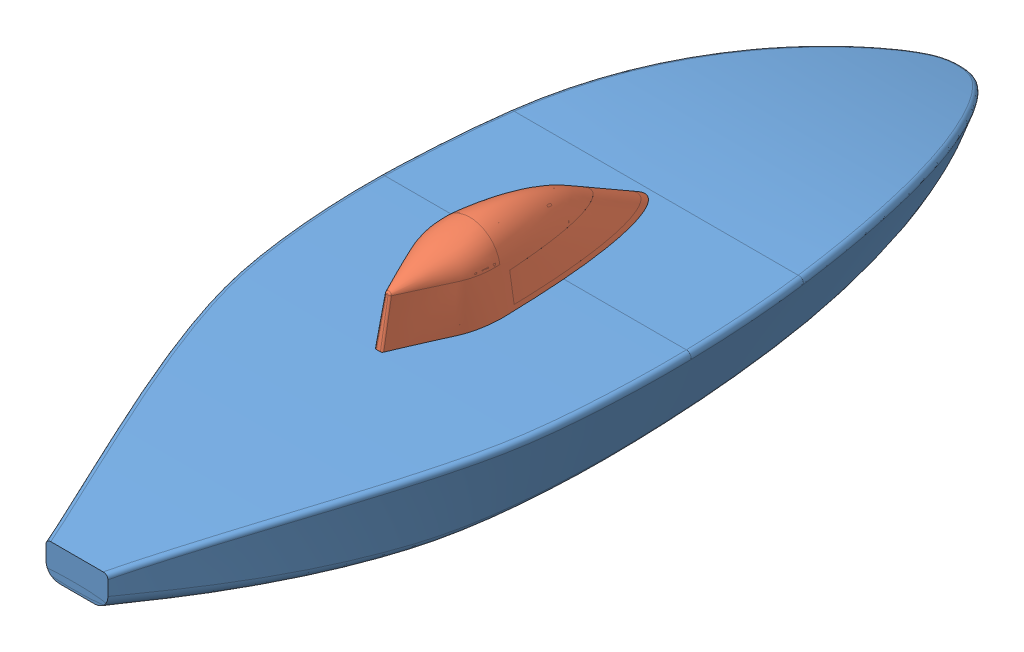
SolidWorks assembly Assem14, configuration Default. Lengths in mm.
Overall size (2274.57 1346.97 5074.75).
2 component instances, 2 part files, 0 mates.
Components (placement in the parent):
- Alain Wide Body (Double Naca, 5 inch high, high nose)-1: Alain Wide Body (Double Naca, 5 inch high, high nose) [Default] at (778.9033 1576.0946 5212.2972) size (2274.57 1216.25 5074.75)
- windshileld4-1: windshileld4 [Default] at (577.2885 1549.3549 2992.3216) x (0 0 1) z (-1 0 0) size (1688.13 400.44 575.69)
